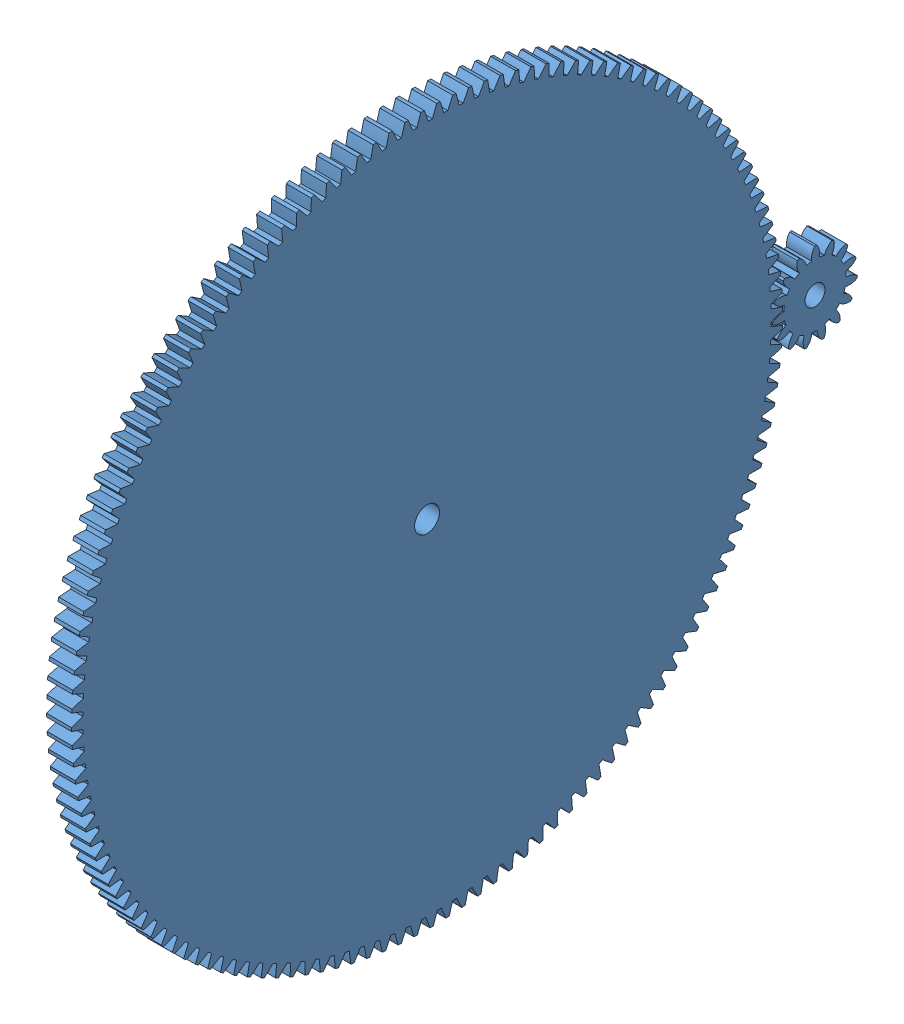
SolidWorks assembly 多圈可變電阻定位齒輪組[01-v1.0], configuration Default. Lengths in mm.
Overall size (5 199.3 199.3).
2 component instances, 1 part files, 3 mates.
Components (placement in the parent):
- spur gear_am-1: spur gear_am [Metric - Spur gear 1M 15T 20PA 5FW ---S15N75H50L4N] at (-23.281 -6.7821 -46.3074) x (1 0 0) z (0 -0.573304 0.819343) size (5 16.86 16.95)
- spur gear_am-2: spur gear_am [Metric - Spur gear 1M 140T 20PA 5FW ---S140N75H50L5N] at (-23.281 -6.7821 31.1926) x (1 0 0) z (0 0.787752 0.615993) size (5 141.98 141.98)
Mates (geometry in assembly coordinates):
- Concentric3: concentric aligned: circle of spur gear_am-1; circle of assembly
- Coincident1: coincident aligned: plane of spur gear_am-1 through (-23.281 -6.7821 -46.3074) normal (-1 0 0); plane of spur gear_am-2 through (-23.281 -6.7821 31.1926) normal (-1 0 0)
- Concentric4: concentric aligned: circle of spur gear_am-2; circle of assembly
